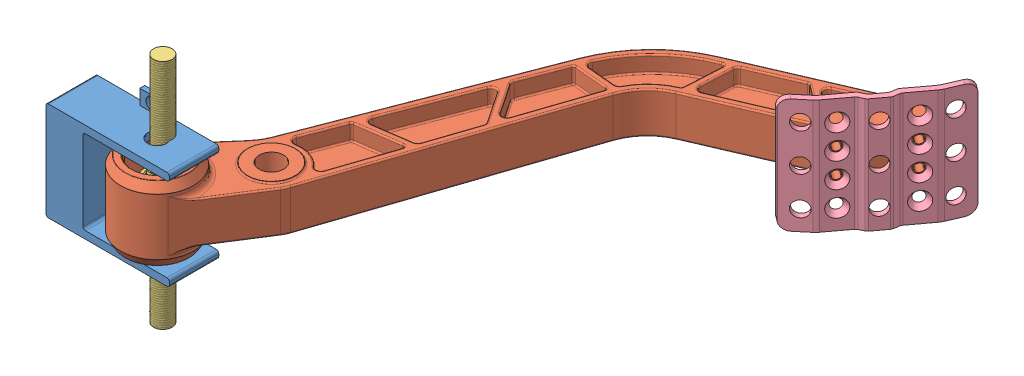
SolidWorks assembly BR22-1100-BASM, configuration Default. Lengths in mm.
Overall size (246.81 121.21 285.11).
4 component instances, 4 part files, 4 mates.
Components (placement in the parent):
- BR22-1103-PRT-1: BR22-1103-PRT [Default] at (2.0099 35.5523 58.5483) size (63.5 66.04 31.75)
- brake_pedal-1: brake_pedal [Default] at (71.5863 60.0099 37.5471) x (0 1 0) z (0.801705 0 0.59772) size (37.97 301.81 72.18)
- Balance bar2022-1: Balance bar2022 [Default] at (46.2202 62.4101 68.0401) size (20.15 121.21 20.15)
- brake_pedal_pad-1: brake_pedal_pad [Default] at (215.4133 89.7279 -130.9159) x (0.59772 0 -0.801705) z (0 -1 0) size (73.98 8.25 58.98)
Mates (geometry in assembly coordinates):
- Concentric2: concentric aligned: circle of BR22-1103-PRT-1; circle of brake_pedal-1
- Concentric3: concentric aligned: circle of brake_pedal-1; circle of brake_pedal_pad-1
- Concentric4: concentric aligned: circle of brake_pedal-1; circle of brake_pedal_pad-1
- Coincident2: coincident anti-aligned: plane of brake_pedal-1 through (225.8076 70.6144 -148.0371) normal (0.801705 0 0.59772); plane of brake_pedal_pad-1 through (218.7676 30.7491 -138.5945) normal (-0.801705 0 -0.59772)
